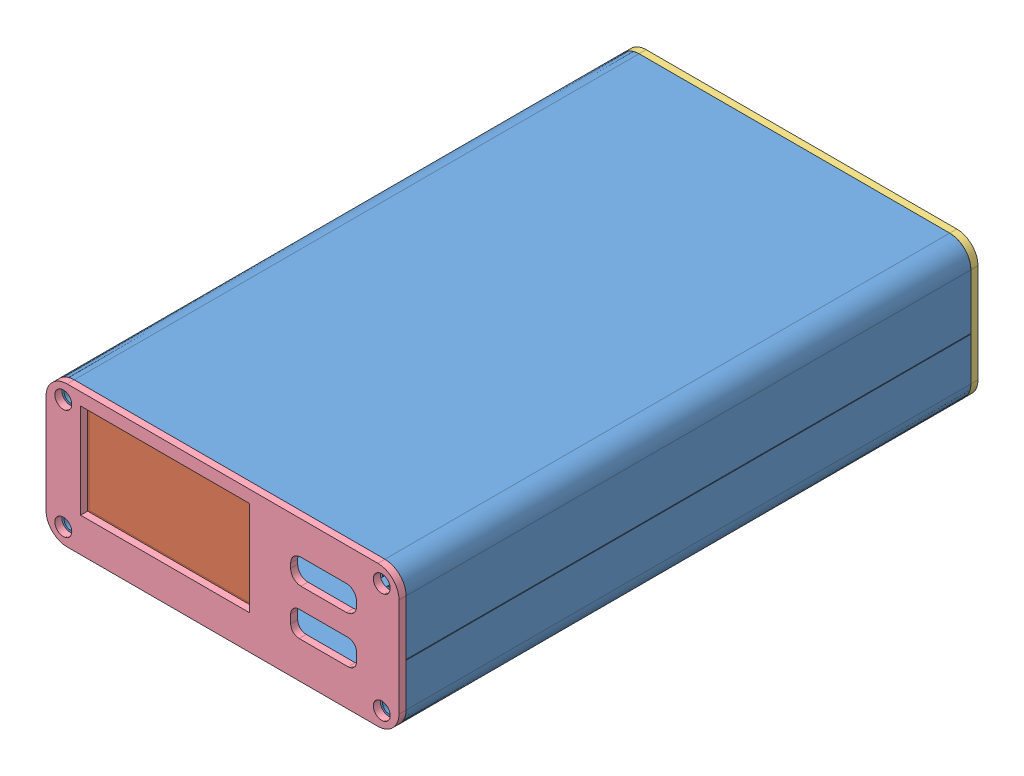
SolidWorks assembly 整机, configuration 默认. Lengths in mm.
Overall size (50 20 82).
7 component instances, 7 part files, 35 mates.
Components (placement in the parent):
- 铝壳2050-1: 铝壳2050 [默认] at (0 0 -80) size (50 20 80)
- OLED TFT 0.96 inch 64x128 monochrome-1: OLED TFT 0.96 inch 64x128 monochrome [Default] at (14.4 21.02 -1.4) x (1 0 0) z (0 -1 0) size (25 1.4 17.64)
- 零件29^整机-1: 零件29^整机 [Default] at origin (virtual)
- 零件30^整机-1: 零件30^整机 [Default] at origin (virtual)
- 零件31^整机-1: 零件31^整机 [Default] at origin (virtual)
- 零件32^整机-1: 零件32^整机 [Default] at (0 0 -80) x (-1 0 0) z (0 0 -1) size (50 20 1) (virtual)
- 零件33^整机-1: 零件33^整机 [Default] at origin size (50 20 1) (virtual)
Mates (geometry in assembly coordinates):
- 重合1: coincident anti-aligned: plane of 铝壳2050-1 through (1.45 16.6 0) normal (0 -1 0); plane of OLED TFT 0.96 inch 64x128 monochrome-1 through (1.9 16.6 -0.1) normal (0 1 0)
- 重合2: coincident aligned: plane of 铝壳2050-1 through (0.55 14.8 0) normal (0 0 1); plane of OLED TFT 0.96 inch 64x128 monochrome-1 through (14.4 21.02 0) normal (0 0 1)
- 在位1: in place: plane of ? through (-29.6538 5.4392 160) normal (0 0 1); plane of ? through (0 0 160) normal (0 0 1); moOrthogonalPlaneRef_w of ? through (-29.6538 5.4392 160) normal (0 0 1); plane of ? through (0 0 160) normal (0 1 0); plane of ? through (-29.6538 5.4392 160) normal (0 0 1); plane of ? through (0 0 160) normal (1 0 0); plane of 铝壳2050-1 through (0.55 14.8 0) normal (0 0 1); unknown of ?
- 重合12: coincident aligned: 
- 重合13: coincident aligned: plane of 铝壳2050-1 through (0 0 0) normal (0 1 0); plane of ? through (0 0 0) normal (0 1 0)
- 重合14: coincident anti-aligned: plane of 铝壳2050-1 through (0 0 0) normal (-1 0 0); plane of ? through (0 0 0) normal (1 0 0)
- 重合3: coincident anti-aligned: plane of 铝壳2050-1 through (46.35 1.7 0) normal (0 1 0); plane of ? through (22.4002 1.7 -39.7234) normal (0 -1 0)
- 重合4: coincident anti-aligned: plane of 铝壳2050-1 through (-1.25 1.7 0) normal (1 0 0); plane of ? through (-1.25 1.7 -0.0252) normal (-1 0 0)
- 重合5: coincident aligned: plane of 铝壳2050-1 through (0.55 14.8 -80) normal (0 0 -1); plane of ? through (-1.25 1.7 -80) normal (0 0 -1)
- 距离1: distance = 0.45 mm anti-aligned: plane of 铝壳2050-1 through (1.45 16.6 0) normal (1 0 0); plane of OLED TFT 0.96 inch 64x128 monochrome-1 through (1.9 16.6 -0.1) normal (-1 0 0)
- 重合10: coincident aligned: plane of 铝壳2050-1 through (0.55 14.8 0) normal (0 0 1); plane of ? through (46.35 12.1 0) normal (0 0 1)
- 重合11: coincident anti-aligned: plane of 铝壳2050-1 through (46.35 13.9 0) normal (-1 0 0); plane of ? through (46.35 12.1 -79.9748) normal (1 0 0)
- 重合12: coincident anti-aligned: plane of 铝壳2050-1 through (46.35 12.1 0) normal (0 1 0); plane of ? through (27.0564 12.1 -39.2694) normal (0 -1 0)
- 重合13: coincident aligned: plane of 铝壳2050-1 through (0.55 14.8 0) normal (0 0 1); plane of ? through (46.35 1.7 0) normal (0 0 1)
- 重合14: coincident anti-aligned: plane of 铝壳2050-1 through (46.35 1.7 0) normal (-1 0 0); plane of ? through (46.35 1.7 -79.9748) normal (1 0 0)
- 重合15: coincident anti-aligned: plane of 铝壳2050-1 through (46.35 1.7 0) normal (0 1 0); plane of ? through (22.5255 1.7 -39.6982) normal (0 -1 0)
- 重合16: coincident anti-aligned: plane of 铝壳2050-1 through (46.35 1.7 0) normal (0 1 0); plane of ? through (22.4255 1.7 -39.6982) normal (0 -1 0)
- 距离2: distance = 0.1 mm: plane of ? through (46.25 1.7 -79.9748) normal (1 0 0); plane of 铝壳2050-1 through (46.35 1.7 0) normal (-1 0 0)
- 重合18: coincident aligned: plane of 铝壳2050-1 through (44.55 0.8 0) normal (0 0 1); plane of ? through (46.25 1.7 0) normal (0 0 1)
- 在位2: in place: plane of 铝壳2050-1 through (44.55 0.8 -80) normal (0 0 -1); plane of 零件32^整机-1 through (0 0 -80) normal (0 0 -1); plane of 铝壳2050-1 through (44.55 0.8 -80) normal (0 0 -1); plane of 零件32^整机-1 through (0 0 -80) normal (0 1 0); plane of 铝壳2050-1 through (44.55 0.8 -80) normal (0 0 -1); plane of 零件32^整机-1 through (0 0 -80) normal (-1 0 0); plane of 铝壳2050-1 through (44.55 0.8 -80) normal (0 0 -1); unknown of 零件32^整机-1
- 重合19: coincident aligned: plane of 铝壳2050-1; plane of 零件32^整机-1
- 重合20: coincident aligned: moOrthogonalPlaneRef_w of 铝壳2050-1 through (0 0 -80) normal (0 1 0); plane of 零件32^整机-1 through (0 0 -80) normal (0 1 0)
- 重合21: coincident anti-aligned: moOrthogonalPlaneRef_w of 铝壳2050-1 through (0 0 -80) normal (1 0 0); plane of 零件32^整机-1 through (0 0 -80) normal (-1 0 0)
- 在位3: in place: plane of 铝壳2050-1 through (0.55 14.8 0) normal (0 0 1); plane of ? through (0 0 0) normal (0 0 1); plane of 铝壳2050-1 through (0.55 14.8 0) normal (0 0 1); plane of ? through (0 0 0) normal (0 1 0); plane of 铝壳2050-1 through (0.55 14.8 0) normal (0 0 1); plane of ? through (0 0 0) normal (1 0 0); plane of 铝壳2050-1 through (0.55 14.8 0) normal (0 0 1); unknown of ?
- 重合22: coincident aligned: plane of 铝壳2050-1; plane of 零件33^整机-1
- 重合23: coincident aligned: moOrthogonalPlaneRef_w of 铝壳2050-1 through (0 0 0) normal (0 1 0); plane of 零件33^整机-1 through (0 0 0) normal (0 1 0)
- 重合24: coincident anti-aligned: moOrthogonalPlaneRef_w of 铝壳2050-1 through (0 0 0) normal (-1 0 0); plane of 零件33^整机-1 through (0 0 0) normal (1 0 0)
- 重合19: coincident aligned: plane of 铝壳2050-1 through (0.55 14.8 0) normal (0 0 1); plane of ? through (46.2506 12.1 0) normal (0 0 1)
- 距离3: distance = 0.1 mm anti-aligned: plane of 铝壳2050-1 through (46.35 13.9 0) normal (-1 0 0); plane of ? through (46.25 12.1 -80.0153) normal (1 0 0)
- 重合22: coincident anti-aligned: plane of 铝壳2050-1 through (46.35 12.1 0) normal (0 1 0); plane of ? through (26.7784 12.1 -38.114) normal (0 -1 0)
- 距离4: distance = 0.25 mm: plane of 3D_1_PCB_YDS-Charger_2022-04-09_2022-04-09-1/3D_1_PCB_YDS-Charger_2022-04-09_2022-04-09.step-1/COMPOUND-19.step-1 through (-1 1.7 -0.0252) normal (-1 0 0); plane of 铝壳2050-1 through (-1.25 1.7 0) normal (1 0 0)
- 重合24: coincident: plane of 铝壳2050-1 through (44.55 0.8 -80) normal (0 0 -1); plane of 3D_1_PCB_YDS-Charger_2022-04-09_2022-04-09-1/3D_1_PCB_YDS-Charger_2022-04-09_2022-04-09.step-1/COMPOUND-19.step-1 through (-1 1.7 -80) normal (0 0 -1)
- 重合25: coincident anti-aligned: plane of 铝壳2050-1 through (-1.25 1.7 0) normal (0 1 0); plane of 3D_1_PCB_YDS-Charger_2022-04-09_2022-04-09-1/3D_1_PCB_YDS-Charger_2022-04-09_2022-04-09.step-1/COMPOUND-19.step-1 through (22.4026 1.7 -39.7223) normal (0 -1 0)
- 重合27: coincident: plane of 铝壳2050-1 through (0.55 14.8 -80) normal (0 0 -1); plane of 3D_2_PCB_Daughter-Board_2022-04-09_2022-04-09-1/3D_2_PCB_Daughter-Board_2022-04-09_2022-04-09.step-1/COMPOUND-4.step-1 through (-1 12.1 -80) normal (0 0 -1)
- 重合28: coincident anti-aligned: plane of 铝壳2050-1 through (-1.25 12.1 0) normal (0 1 0); plane of 3D_2_PCB_Daughter-Board_2022-04-09_2022-04-09-1/3D_2_PCB_Daughter-Board_2022-04-09_2022-04-09.step-1/COMPOUND-4.step-1 through (22.9795 12.1 -38.3669) normal (0 -1 0)
